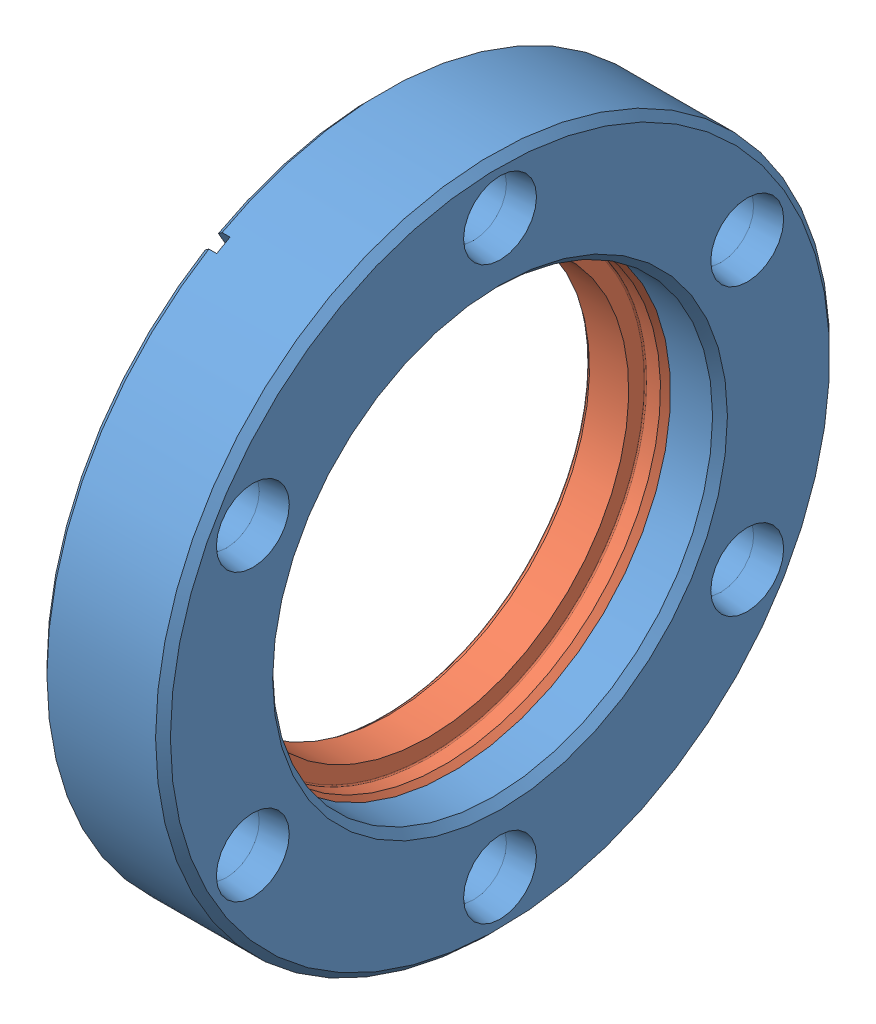
SolidWorks assembly 100043, configuration Default. Lengths in mm.
Overall size (12.71 69.34 69.34).
2 component instances, 2 part files, 2 mates.
Components (placement in the parent):
- 990363-1: 990363 [Default] at (10.4554 39.0797 56.0526) size (12.71 69.34 69.34)
- 990367-1: 990367 [Default] at (11.1158 39.0797 56.0526) x (1 0 0) z (0 0.094755 0.995501) size (6.91 48.06 48.06)
Mates (geometry in assembly coordinates):
- Concentric1: concentric: cylinder of 990363-1 through (10.4554 39.0797 56.0526) axis (-1 0 0) radius 34.671; cylinder of 990367-1 through (11.1158 39.0797 56.0526) axis (-1 0 0) radius 24.0284
- Coincident1: coincident anti-aligned: plane of 990363-1 through (18.0754 63.2351 56.0526) normal (-1 0 0); plane of 990367-1 through (18.0754 63 53.7758) normal (1 0 0)
